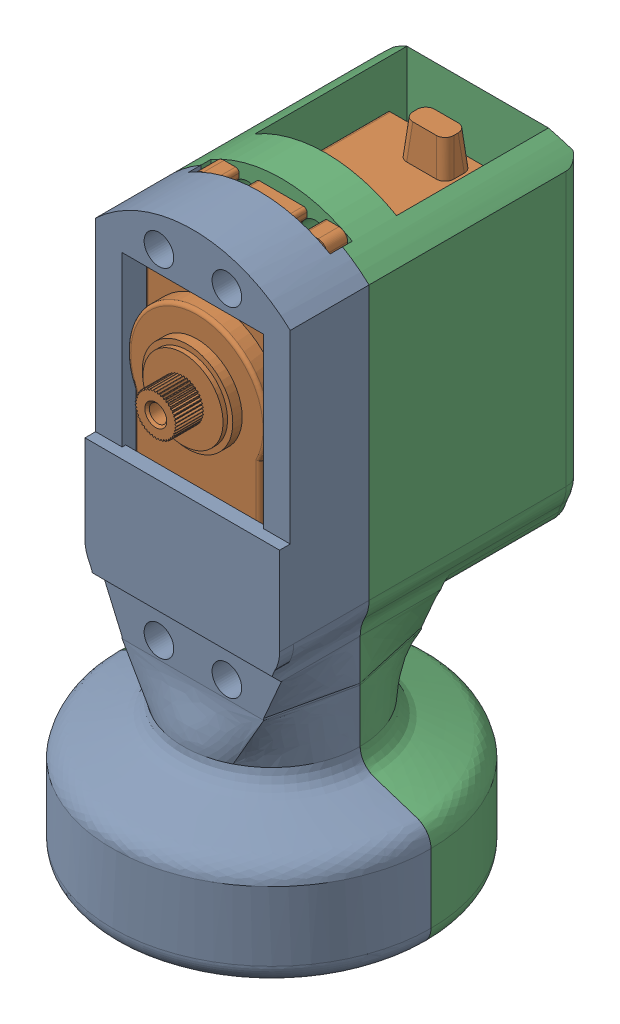
SolidWorks assembly Link1andMotorAssem, configuration Default. Lengths in mm.
Overall size (45.77 83.87 53.72).
3 component instances, 3 part files, 6 mates.
Components (placement in the parent):
- Link1Half-1: Link1Half [Default] at origin size (45.77 83.87 22.94)
- MG995_Servo-1: MG995_Servo [Default] at (0 54.675 -29.06) x (0 -1 0) z (-1 0 0) size (54.65 45.7 20.01)
- Link1Half2nd-1: Link1Half2nd [Default] x (-1 0 0) z (0 0 -1) size (45.77 83.87 30.89)
Mates (geometry in assembly coordinates):
- Concentric3: concentric anti-aligned: circle of MG995_Servo-1
- Distance1: distance = 0.01 mm anti-aligned: plane of Link1Half-1 through (0 0 1.6) normal (0 0 -1); plane of MG995_Servo-1 through (0 54.675 1.59) normal (0 0 1)
- Parallel5: parallel anti-aligned: plane of Link1Half-1 through (10.16 26.416 1.6) normal (0 1 0); plane of MG995_Servo-1 through (10 34.55 -1.41) normal (0 -1 0)
- Coincident1: coincident anti-aligned: plane of Link1Half-1 through (-22.86 5.08 0) normal (0 0 -1); plane of Link1Half2nd-1 through (22.86 5.08 0) normal (0 0 1)
- Coincident2: coincident aligned: plane of Link1Half-1 through (0 0 0) normal (0 -1 0); plane of Link1Half2nd-1 through (0 0 0) normal (0 -1 0)
- Coincident3: coincident aligned: line of Link1Half-1 through (22.86 12.7 0) axis (0 -1 0); line of Link1Half2nd-1 through (22.86 12.7 0) axis (0 -1 0)
